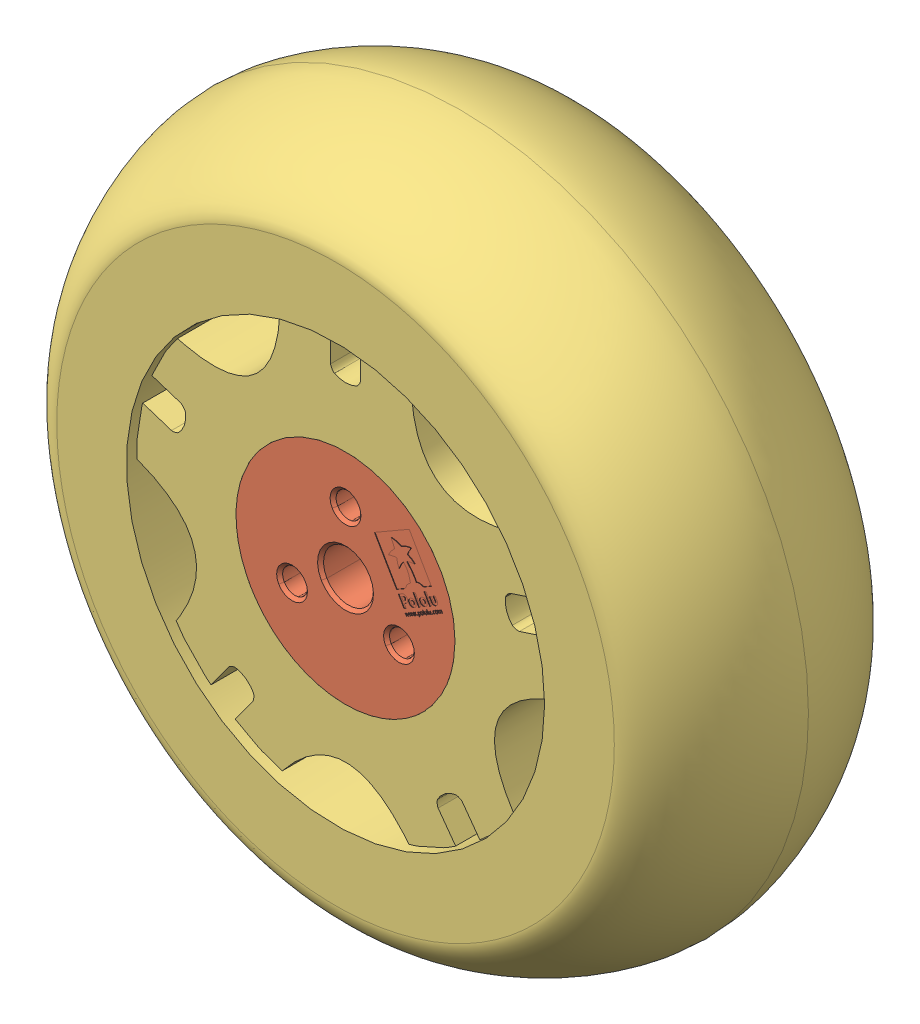
SolidWorks assembly Assemblage 5mm, configuration Défaut. Lengths in mm.
Overall size (70.03 70.03 25.12).
3 component instances, 3 part files, 5 mates.
Components (placement in the parent):
- moyeu pololu (axe 5mm) part 2-1: moyeu pololu (axe 5mm) part 2 [Défaut] at (16.3796 8.0597 10.6516) size (21.9 21.9 3)
- moyeux pololu (axe 5mm)-1: moyeux pololu (axe 5mm) [Défaut] at (16.3796 8.0597 27.1516) x (0.866025 0.5 0) z (0 0 1) size (22 22 12)
- Roue Scooter noire 70x25 mm 3272-1: Roue Scooter noire 70x25 mm 3272 [Défaut] at (16.3796 8.0597 22.1516) size (70.03 70.03 25.12)
Mates (geometry in assembly coordinates):
- Coaxiale1: concentric aligned: cylinder of moyeux pololu (axe 5mm)-1 through (16.3796 8.0597 33.6516) axis (0 0 -1) radius 11; cylinder of Roue Scooter noire 70x25 mm 3272-1 through (16.3796 8.0597 34.6516) axis (0 0 -1) radius 11
- Coïncidente1: coincident anti-aligned: plane of moyeux pololu (axe 5mm)-1 through (16.3796 8.0597 33.6516) normal (0 0 1); circle of Roue Scooter noire 70x25 mm 3272-1
- Coaxiale2: concentric aligned: cylinder of moyeu pololu (axe 5mm) part 2-1 through (16.3796 8.0597 13.6516) axis (0 0 -1) radius 10.95; cylinder of Roue Scooter noire 70x25 mm 3272-1 through (16.3796 8.0597 34.6516) axis (0 0 -1) radius 11
- Coïncidente2: coincident aligned: plane of moyeu pololu (axe 5mm) part 2-1 through (16.3796 8.0597 10.6516) normal (0 0 -1); plane of Roue Scooter noire 70x25 mm 3272-1 through (16.3796 8.0597 10.6516) normal (0 0 -1)
- Coaxiale3: concentric aligned: cylinder of moyeu pololu (axe 5mm) part 2-1 through (11.0103 4.9597 13.6516) axis (0 0 -1) radius 1.6; cylinder of moyeux pololu (axe 5mm)-1 through (11.0103 4.9597 33.6516) axis (0 0 -1) radius 1.25
